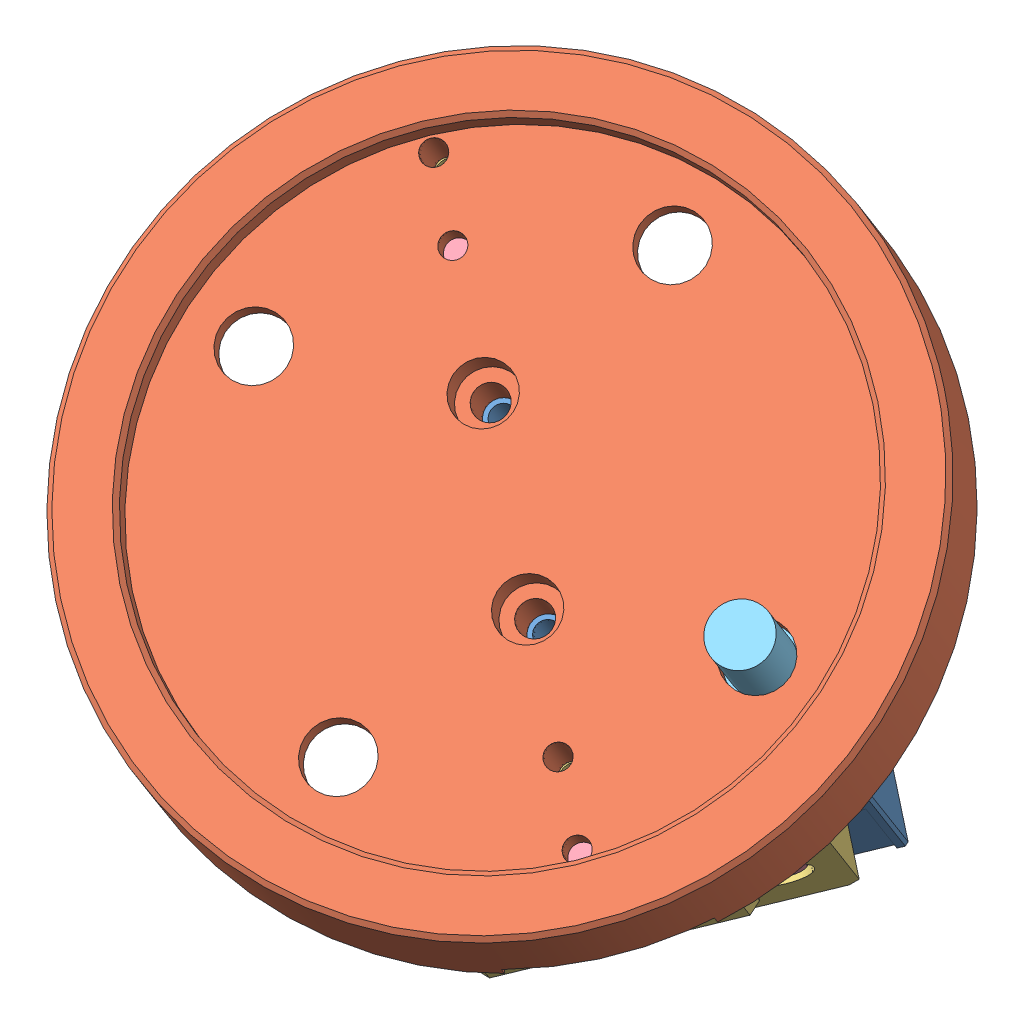
SolidWorks assembly 工业手抓, configuration 默认. Lengths in mm.
Overall size (108.93 122.61 127.38).
8 component instances, 5 part files, 20 mates.
Components (placement in the parent):
- Z-EFG-8NK-HW-1: Z-EFG-8NK-HW [默认] at (774.146 457.7755 169.9566) x (-0.335475 -0.736101 -0.587887) z (0.67277 -0.624033 0.397447) size (93.9 42.01 24)
- 法兰连接板-1: 法兰连接板 [默认] at (758.3449 422.4929 142.039) x (-0.67277 0.624033 -0.397447) z (0.659422 0.262179 -0.704574) size (75 12 75)
- 连接板-1: 连接板 [默认] at (789.8049 403.798 147.4948) x (-0.659422 -0.262179 0.704574) z (0.67277 -0.624033 0.397447) size (24 70 23)
- 连接板-2: 连接板 [默认] at (726.8849 441.1879 136.5833) x (0.659422 0.262179 -0.704574) z (-0.67277 0.624033 -0.397447) size (24 70 23)
- SCB3-8-1: SCB3-8 [Default] at (777.9912 402.5942 153.0218) x (0.335475 0.736101 0.587887) z (-0.57731 -0.332496 0.745761) size (11 5.5 5.5)
- SCB6-10-1: SCB6-10 [Default] at (784.1762 421.1017 140.6074) x (0.335475 0.736101 0.587887) z (-0.57731 -0.332496 0.745761) size (22 10 10)
- SCB3-8-2: SCB3-8 [Default] at (750.9813 370.072 106.4156) x (-0.67277 0.624033 -0.397447) z (-0.194114 -0.66726 -0.719085) size (11 5.5 5.5)
- SCB3-8-3: SCB3-8 [Default] at (743.0072 435.0439 132.3546) x (0.335475 0.736101 0.587887) z (-0.642255 0.635253 -0.428909) size (11 5.5 5.5)
Mates (geometry in assembly coordinates):
- 同心40: concentric: cylinder of assembly; cylinder of assembly; cylinder of Z-EFG-8NK-HW-1 through (752.0546 428.2228 138.284) axis (-0.335475 -0.736101 -0.587887) radius 1.2295; cylinder of 法兰连接板-1 through (755.1074 434.9214 143.6338) axis (0.335475 0.736101 0.587887) radius 1.7
- 同心41: concentric: cylinder of assembly; cylinder of assembly; cylinder of Z-EFG-8NK-HW-1 through (764.5681 416.6158 145.6765) axis (-0.335475 -0.736101 -0.587887) radius 1.2295; cylinder of 法兰连接板-1 through (767.6209 423.3143 151.0263) axis (0.335475 0.736101 0.587887) radius 1.7
- 重合308: coincident: plane of assembly; plane of assembly; plane of Z-EFG-8NK-HW-1 through (758.3449 422.4929 142.039) normal (0.335475 0.736101 0.587887); plane of 法兰连接板-1 through (758.3449 422.4929 142.039) normal (-0.335475 -0.736101 -0.587887)
- 重合310: coincident: plane of assembly; plane of assembly; plane of Z-EFG-8NK-HW-1 through (737.4047 369.1141 123.8675) normal (0.67277 -0.624033 0.397447); plane of 连接板-1 through (758.5051 411.8584 155.2633) normal (-0.67277 0.624033 -0.397447)
- 重合311: coincident: plane of assembly; plane of assembly; plane of Z-EFG-8NK-HW-1 through (737.4047 369.1141 123.8675) normal (0.67277 -0.624033 0.397447); plane of 连接板-1 through (758.5051 411.8584 155.2633) normal (-0.67277 0.624033 -0.397447)
- 同心43: concentric: cylinder of assembly; cylinder of assembly; cylinder of Z-EFG-8NK-HW-1 through (749.8376 371.1328 105.7399) axis (-0.67277 0.624033 -0.397447) radius 1.2295; cylinder of 连接板-1 through (753.2688 367.9503 107.7669) axis (0.67277 -0.624033 0.397447) radius 1.7
- 同心44: concentric: cylinder of assembly; cylinder of assembly; cylinder of Z-EFG-8NK-HW-1 through (741.2652 367.7245 114.8994) axis (-0.67277 0.624033 -0.397447) radius 1.2295; cylinder of 连接板-1 through (744.6963 364.5419 116.9264) axis (0.67277 -0.624033 0.397447) radius 1.7
- 重合313: coincident: plane of assembly; plane of assembly; plane of Z-EFG-8NK-HW-1 through (741.0409 391.9562 93.1915) normal (-0.67277 0.624033 -0.397447); plane of 连接板-2 through (758.1847 433.1275 128.8148) normal (0.67277 -0.624033 0.397447)
- 同心46: concentric: cylinder of assembly; cylinder of assembly; cylinder of Z-EFG-8NK-HW-1 through (733.8257 385.9848 96.2807) axis (0.67277 -0.624033 0.397447) radius 1.2295; cylinder of 连接板-2 through (730.3946 389.1674 94.2537) axis (-0.67277 0.624033 -0.397447) radius 1.7
- 重合309: coincident: plane of assembly; plane of assembly; plane of 法兰连接板-1 through (758.3449 422.4929 142.039) normal (-0.335475 -0.736101 -0.587887); plane of 连接板-1 through (773.9788 397.5056 164.4046) normal (0.335475 0.736101 0.587887)
- 重合314: coincident: plane of assembly; plane of assembly; plane of 法兰连接板-1 through (758.3449 422.4929 142.039) normal (-0.335475 -0.736101 -0.587887); plane of 连接板-2 through (742.711 447.4802 119.6735) normal (0.335475 0.736101 0.587887)
- 同心45: concentric: cylinder of assembly; cylinder of assembly; cylinder of 法兰连接板-1 through (743.5439 436.2217 133.2952) axis (-0.335475 -0.736101 -0.587887) radius 1.25; cylinder of 连接板-2 through (741.8666 432.5411 130.3558) axis (-0.335475 -0.736101 -0.587887) radius 3
- 同心48: concentric: cylinder of assembly; cylinder of assembly; cylinder of 法兰连接板-1 through (781.8949 416.0962 136.6097) axis (-0.335475 -0.736101 -0.587887) radius 5.5; cylinder of SCB6-10-1 through (782.1633 416.6851 137.08) axis (-0.335475 -0.736101 -0.587887) radius 3
- 重合316: coincident: circle of 法兰连接板-1; unknown of ?
- 同心47: concentric: cylinder of assembly; cylinder of assembly; cylinder of 连接板-1 through (776.8506 400.0915 151.023) axis (-0.335475 -0.736101 -0.587887) radius 1.7; cylinder of SCB3-8-1 through (776.9848 400.3859 151.2582) axis (-0.335475 -0.736101 -0.587887) radius 1.5
- 重合315: coincident: plane of 连接板-1 through (776.8702 402.1485 154.2196) normal (-0.335475 -0.736101 -0.587887); unknown of ?
- 同心49: concentric: cylinder of assembly; cylinder of assembly; cylinder of 连接板-1 through (753.2688 367.9503 107.7669) axis (0.67277 -0.624033 0.397447) radius 1.7; cylinder of SCB3-8-2 through (752.9997 368.1999 107.6079) axis (0.67277 -0.624033 0.397447) radius 1.5
- 重合317: coincident: plane of assembly; circle of assembly; plane of 连接板-1 through (749.8603 369.6263 107.6134) normal (0.67277 -0.624033 0.397447); circle of SCB3-8-2
- 重合318: coincident: plane of 连接板-2 through (744.1282 435.4896 131.1568) normal (-0.335475 -0.736101 -0.587887); unknown of ?
- 同心50: concentric: cylinder of assembly; cylinder of assembly; cylinder of 连接板-2 through (741.8666 432.5411 130.3558) axis (-0.335475 -0.736101 -0.587887) radius 3; cylinder of SCB3-8-3 through (742.0008 432.8356 130.5909) axis (-0.335475 -0.736101 -0.587887) radius 2.75
